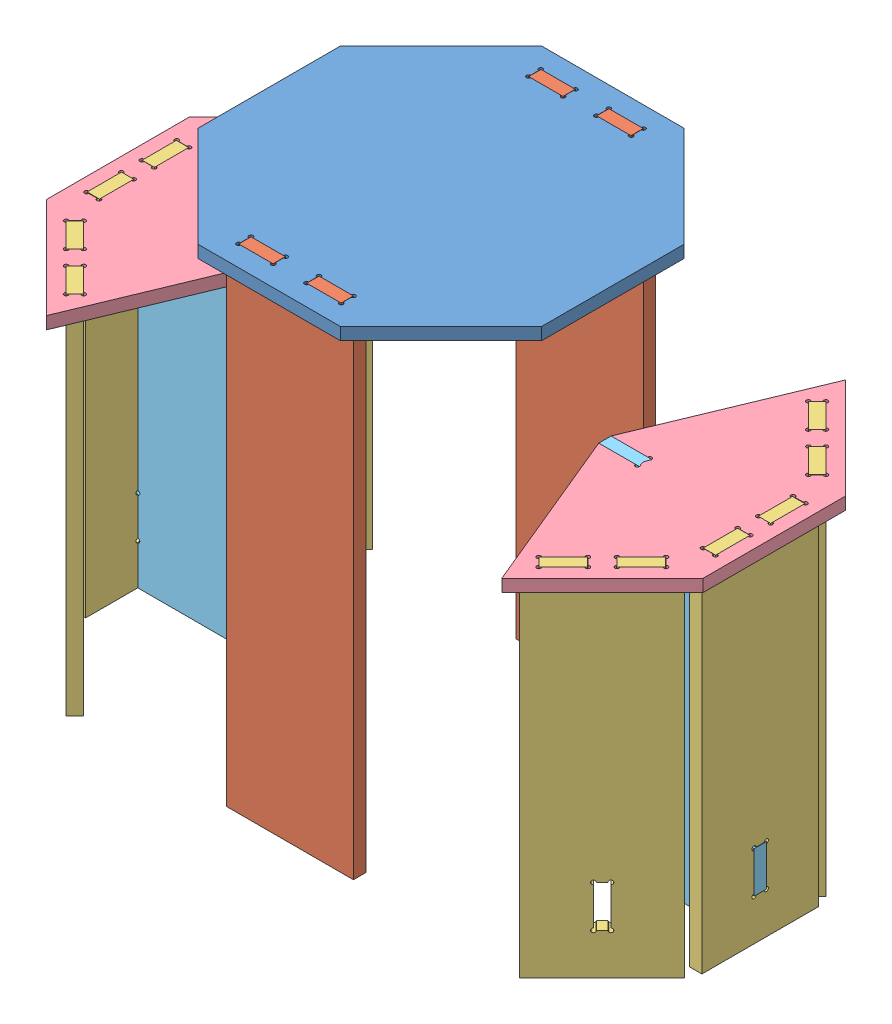
SolidWorks assembly ChessTable, configuration Default. Lengths in mm.
Overall size (955.32 718 500).
16 component instances, 5 part files, 7 mates.
Components (placement in the parent):
- Table_Assembly-1: Table_Assembly [Default] at (216.7195 460.6589 385.0855) size (500 718 500)
  - Table_Top-1: Table_Top [Default] at (-74.0195 4.9518 29.5804) size (500 18 500)
  - Part2-1: Part2 [Default] at (0 0.8658 -30) size (185 718 18)
  - Part2-2: Part2 [Default] at (0 0.8658 -452) size (185 718 18)
- ChairASSLY-1: ChairASSLY [Default] at (-402.1598 584.6238 819.5533) size (246.27 518 500)
  - Part1-1: Part1 [Default] at (991.7789 -819.0131 -319.6373) size (18 518 170)
  - Part5-1: Part5 [Default] at (12065.9695 -301.0131 1743.1464) size (246.27 18 500)
  - Part1-2: Part1 [Default] at (869.4047 -819.0131 -194.6999) x (0.707107 0 0.707107) z (-0.707107 0 0.707107) size (18 518 170)
  - Part1-3: Part1 [Default] at (989.6128 -819.0131 -494.8667) x (0.707107 0 -0.707107) z (0.707107 0 0.707107) size (18 518 170)
  - Stiffener-1: Stiffener [Default] at (-1515.4967 -62.9023 94.9374) size (226.27 518 18)
- ChairASSLY-2: ChairASSLY [Default] at (702.0736 584.6238 9.7786) x (-1 0 0) z (0 0 -1) size (246.27 518 500)
  - Part1-1: Part1 [Default] at (991.7789 -819.0131 -319.6373) size (18 518 170)
  - Part5-1: Part5 [Default] at (12065.9695 -301.0131 1743.1464) size (246.27 18 500)
  - Part1-2: Part1 [Default] at (869.4047 -819.0131 -194.6999) x (0.707107 0 0.707107) z (-0.707107 0 0.707107) size (18 518 170)
  - Part1-3: Part1 [Default] at (989.6128 -819.0131 -494.8667) x (0.707107 0 -0.707107) z (0.707107 0 0.707107) size (18 518 170)
  - Stiffener-1: Stiffener [Default] at (-1515.4967 -62.9023 94.9374) size (226.27 518 18)
Mates (geometry in assembly coordinates):
- Coincident1: coincident aligned: plane of Table_Assembly-1/Part2-1 through (50.1999 -234.3893 616.6659) normal (0 -1 0); plane of ChairASSLY-1/Part1-2 through (600.181 -234.3893 517.3732) normal (0 -1 0)
- Coincident2: coincident aligned: plane of Table_Assembly-1/Part2-2 through (50.1999 -234.3893 194.6659) normal (0 -1 0); plane of ChairASSLY-2/Part1-2 through (-300.2671 -234.3893 311.9587) normal (0 -1 0)
- Parallel1: parallel aligned: plane of Table_Assembly-1/Table_Top-1 through (392.6999 483.6107 518.2193) normal (1 0 0); plane of ChairASSLY-1/Part5-1 through (627.6191 265.6107 311.1125) normal (1 0 0)
- Parallel2: parallel aligned: plane of Table_Assembly-1/Table_Top-1 through (-107.3001 483.6107 311.1125) normal (-1 0 0); plane of ChairASSLY-2/Part5-1 through (-327.7053 265.6107 518.2193) normal (-1 0 0)
- Coincident5: coincident anti-aligned: plane of Table_Assembly-1/Table_Top-1 through (142.6999 465.6107 414.6659) normal (0 0 1); plane of ChairASSLY-1 through (-402.1598 584.6238 414.6659) normal (0 0 -1)
- Coincident6: coincident anti-aligned: plane of Table_Assembly-1/Table_Top-1 through (142.6999 465.6107 414.6659) normal (0 0 1); plane of ChairASSLY-1 through (-402.1598 584.6238 414.6659) normal (0 0 -1)
- Coincident7: coincident aligned: plane of Table_Assembly-1/Table_Top-1 through (142.6999 465.6107 414.6659) normal (0 0 1); plane of ChairASSLY-2 through (702.0736 584.6238 414.6659) normal (0 0 1)
